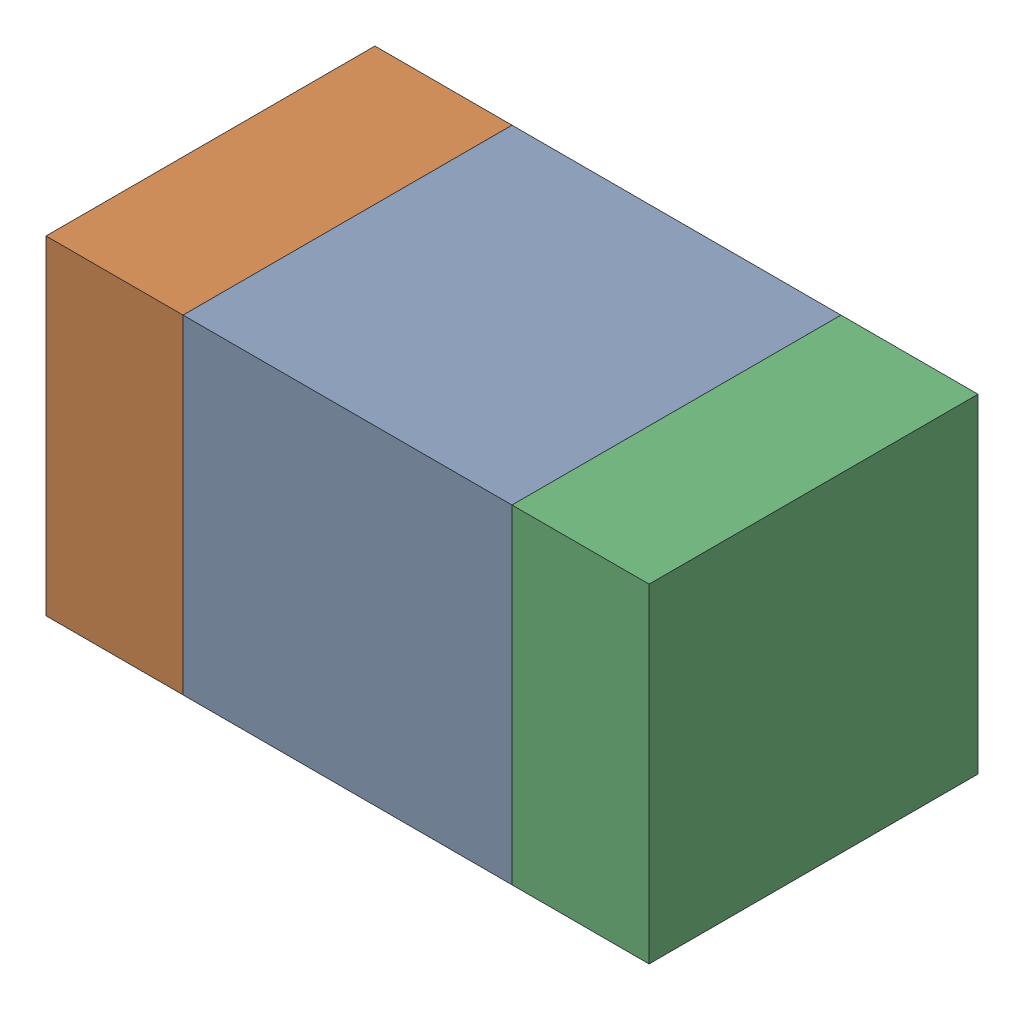
SolidWorks assembly C324_1PCB, configuration Default. Lengths in mm.
Overall size (1.1 0.6 0.6).
6 component instances, 2 part files, 0 mates.
Components (placement in the parent):
- 761606048-1: 761606048 [Default] at (136.5343 120.35 -2.2638) size (0.6 0.6 0.6)
  - Extruded_9-1: Extruded_9 [Default] at origin size (0.6 0.6 0.6)
- 854785160-1: 854785160 [Default] at (136.1093 120.35 -2.2638) size (0.25 0.6 0.6)
  - Extruded_19-1: Extruded_19 [Default] at origin size (0.25 0.6 0.6)
- 854785160-2: 854785160 [Default] at (136.9593 120.35 -2.2638) size (0.25 0.6 0.6)
  - Extruded_19-1: Extruded_19 [Default] at origin size (0.25 0.6 0.6)
